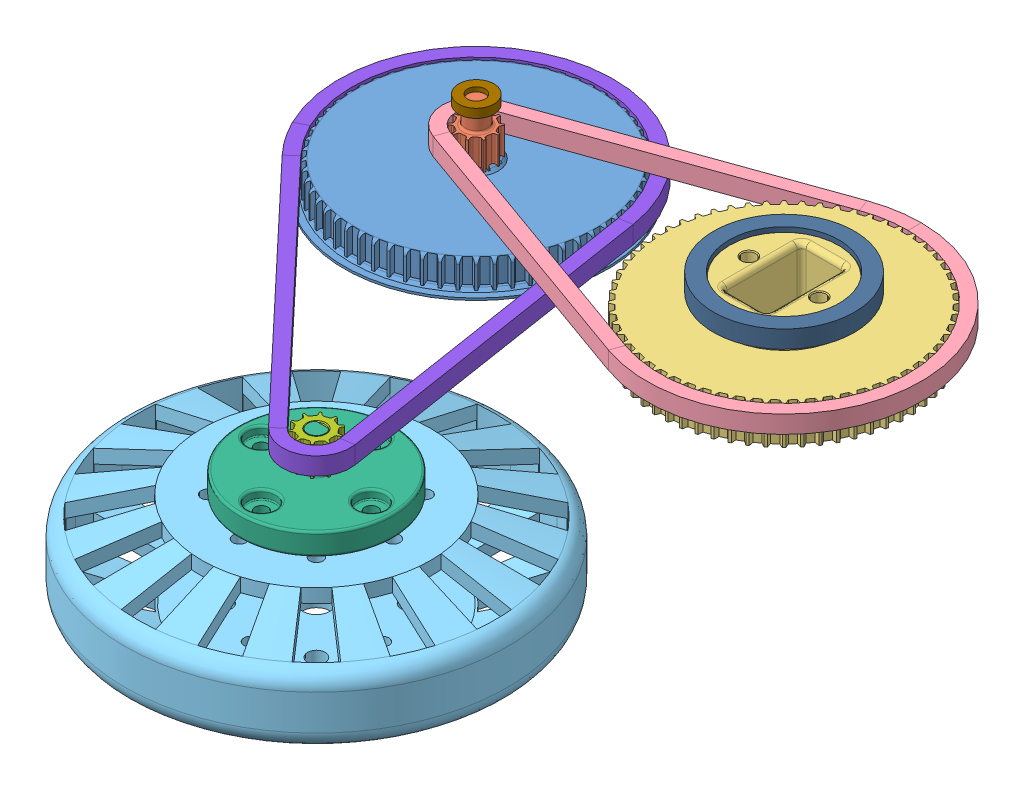
SolidWorks assembly Large_Motor_Pulley_System_Output, configuration Default. Lengths in mm.
Overall size (143.04 56.2 156.68).
14 component instances, 10 part files, 23 mates.
Components (placement in the parent):
- Small_Pulley_Large_Pulley-1: Small_Pulley_Large_Pulley [Default] at (-35 -6.3 -71.381) x (0 0 -1) z (0 -1 0) size (60 60 20.5)
  - transmission_pulley_at3_t60_center-1: transmission_pulley_at3_t60_center [Standard] at origin size (60 60 7.63)
  - transmission_pulley_at3_t10_motor_no_hub-1: transmission_pulley_at3_t10_motor_no_hub [Standard] x (0.135506 0.990777 0) z (-0.990777 0.135506 0) size (9.14 20.5 8.82)
- transmission_pulley_at3_t60_output-1: transmission_pulley_at3_t60_output [Standard] at (35 2.35 -71.381) x (-1 0 0) z (0 -1 0) size (56.43 56.43 18.7)
- Timing Belt-2: Timing Belt [Default] at (-35 4.7 -71.381) size (108.94 4 62.48)
- Shaft_Small_Pulley_Large_Motor-1: Shaft_Small_Pulley_Large_Motor [Default] at (0 -25.25 0) size (87 54.2 87)
  - Large_Motor-1: Large_Motor [Default] at origin size (87 30.6 87)
  - Shaft_Flange_Small_Pulley_For_Large_Motor-1: Shaft_Flange_Small_Pulley_For_Large_Motor [Default] at (0 17.25 0) size (35 23.7 35)
  - transmission_pulley_at3_t10_motor-1: transmission_pulley_at3_t10_motor [Standard] at (0 18.55 0) x (0 0 -1) z (1 0 0) size (9.14 6.7 8.82)
- Timing Belt 79.5 mm-1: Timing Belt 79.5 mm [Default] at (0 -2 0) x (-0.440252 0 -0.897874) z (0.897874 0 -0.440252) size (118.44 4 62.48)
- Bearing 4x8x2-1: Bearing 4x8x2 [Default] at (-35 10.7 -71.381) size (8 2 8)
- Bearing 4x8x2-2: Bearing 4x8x2 [Default] at (-35 -7.8 -71.381) x (0.837169 0 0.546944) z (0.546944 0 -0.837169) size (8 2 8)
- Bearing 32x25x4-1: Bearing 32x25x4 [Default] at (35 -7 -71.381) size (32 4 32)
- Bearing 32x25x4-2: Bearing 32x25x4 [Default] at (35 8.7 -71.381) x (0.999549 0 0.030039) z (-0.030039 0 0.999549) size (32 4 32)
Mates (geometry in assembly coordinates):
- Coincident4: coincident aligned: plane of Small_Pulley_Large_Pulley-1/transmission_pulley_at3_t60_center-1 through (-7.76 0 -71.381) normal (0 1 0)
- Coincident8: coincident aligned: plane of Small_Pulley_Large_Pulley-1/transmission_pulley_at3_t10_motor_no_hub-1 through (-35 6.7 -71.381) normal (0 1 0); plane of transmission_pulley_at3_t60_output-1 through (35 6.7 -99.621) normal (0 1 0)
- Concentric4: concentric aligned: circle of Timing Belt-2; circle of Small_Pulley_Large_Pulley-1/transmission_pulley_at3_t10_motor_no_hub-1
- Coincident9: coincident aligned: plane of Small_Pulley_Large_Pulley-1/transmission_pulley_at3_t10_motor_no_hub-1 through (-35 6.7 -71.381) normal (0 1 0); plane of Timing Belt-2 through (-37.5894 6.7 -64.1295) normal (0 1 0)
- Concentric5: concentric anti-aligned: circle of transmission_pulley_at3_t60_output-1; circle of Timing Belt-2
- Coincident10: coincident aligned: plane of transmission_pulley_at3_t60_output-1 through (35 6.7 -99.621) normal (0 1 0); plane of Timing Belt-2 through (24.4944 6.7 -41.9604) normal (0 1 0)
- Coincident11: coincident aligned: plane of Shaft_Small_Pulley_Large_Motor-1 through (0 -25.25 0) normal (0 0 1)
- Coincident12: coincident aligned: plane of Shaft_Small_Pulley_Large_Motor-1/transmission_pulley_at3_t10_motor-1 through (0 0 0) normal (0 1 0)
- Coincident13: coincident aligned: plane of Shaft_Small_Pulley_Large_Motor-1 through (0 -25.25 0) normal (1 0 0)
- Concentric6: concentric aligned: circle of Shaft_Small_Pulley_Large_Motor-1/transmission_pulley_at3_t10_motor-1; circle of Timing Belt 79.5 mm-1
- Coincident15: coincident aligned: plane of Shaft_Small_Pulley_Large_Motor-1/transmission_pulley_at3_t10_motor-1 through (0 0 0) normal (0 1 0); plane of Timing Belt 79.5 mm-1 through (7.6074 0 -1.1908) normal (0 1 0)
- Coincident16: coincident aligned: plane of Small_Pulley_Large_Pulley-1/transmission_pulley_at3_t60_center-1 through (-7.76 0 -71.381) normal (0 1 0); plane of Timing Belt 79.5 mm-1 through (-63.0496 0 -57.6276) normal (0 1 0)
- Concentric7: concentric aligned: circle of Small_Pulley_Large_Pulley-1/transmission_pulley_at3_t60_center-1; circle of Timing Belt 79.5 mm-1
- Distance1: distance = 35 mm anti-aligned: plane of transmission_pulley_at3_t60_output-1 through (35 2.35 -71.381) normal (-1 0 0)
- Distance2: distance = 35 mm aligned: plane of Small_Pulley_Large_Pulley-1/transmission_pulley_at3_t60_center-1 through (-35 -6.3 -71.381) normal (1 0 0)
- Distance4: distance = 1 mm aligned: plane of Small_Pulley_Large_Pulley-1/transmission_pulley_at3_t10_motor_no_hub-1 through (-35 11.7 -71.381) normal (0 1 0); plane of Bearing 4x8x2-1 through (-35 12.7 -71.381) normal (0 1 0)
- Concentric11: concentric aligned: circle of Small_Pulley_Large_Pulley-1/transmission_pulley_at3_t10_motor_no_hub-1; circle of Bearing 4x8x2-1
- Distance5: distance = 1 mm anti-aligned: plane of Bearing 4x8x2-2 through (-35 -7.8 -71.381) normal (0 1 0); plane of Small_Pulley_Large_Pulley-1/transmission_pulley_at3_t10_motor_no_hub-1 through (-35 -8.8 -71.381) normal (0 -1 0)
- Concentric8: concentric anti-aligned: circle of Small_Pulley_Large_Pulley-1/transmission_pulley_at3_t10_motor_no_hub-1; circle of Bearing 4x8x2-2
- Concentric9: concentric anti-aligned: circle of transmission_pulley_at3_t60_output-1; circle of Bearing 32x25x4-1
- Coincident20: coincident anti-aligned: plane of transmission_pulley_at3_t60_output-1 through (35 -3 -71.381) normal (0 -1 0); plane of Bearing 32x25x4-1 through (35 -3 -71.381) normal (0 1 0)
- Concentric10: concentric aligned: circle of transmission_pulley_at3_t60_output-1; circle of Bearing 32x25x4-2
- Coincident21: coincident anti-aligned: plane of transmission_pulley_at3_t60_output-1 through (35 8.7 -71.381) normal (0 1 0); plane of Bearing 32x25x4-2 through (35 8.7 -71.381) normal (0 -1 0)
